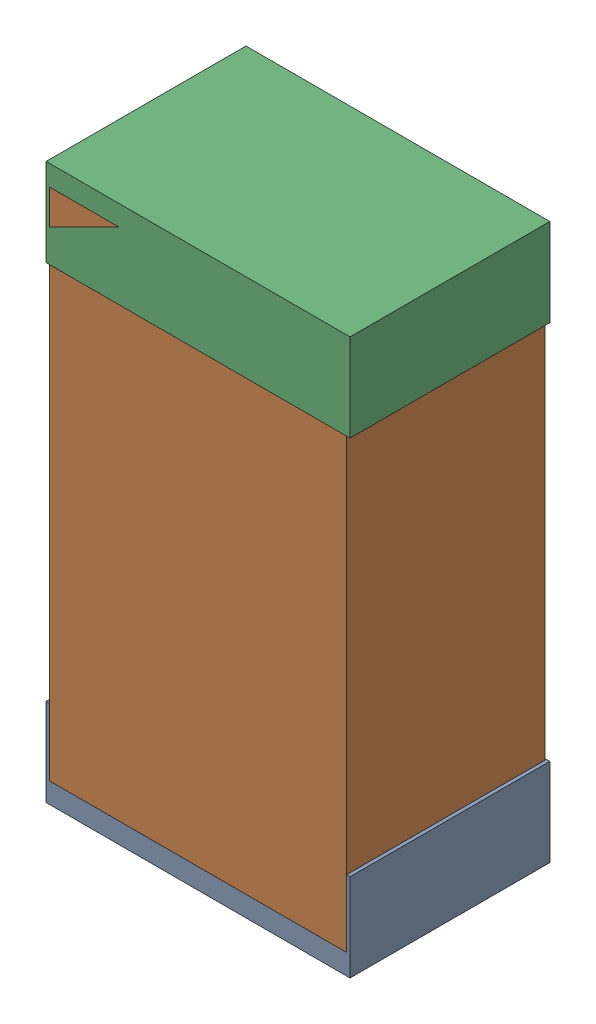
SolidWorks assembly R40Kanaloa_v2.0.0_Motor, configuration Default. Lengths in mm.
Overall size (1.3 2.38 0.85).
6 component instances, 2 part files, 0 mates.
Components (placement in the parent):
- 330415056-1: 330415056 [Default] at (96.52 120.92 -1.9574) size (1.3 0.38 0.85)
  - Extruded_2-1: Extruded_2 [Default] at origin size (1.3 0.38 0.85)
- 334787376-1: 334787376 [Default] at (96.52 121.92 -1.9524) size (1.27 2.2 0.85)
  - Extruded_16-1: Extruded_16 [Default] at origin size (1.27 2.2 0.85)
- 330415056-2: 330415056 [Default] at (96.52 122.92 -1.9574) size (1.3 0.38 0.85)
  - Extruded_2-1: Extruded_2 [Default] at origin size (1.3 0.38 0.85)
